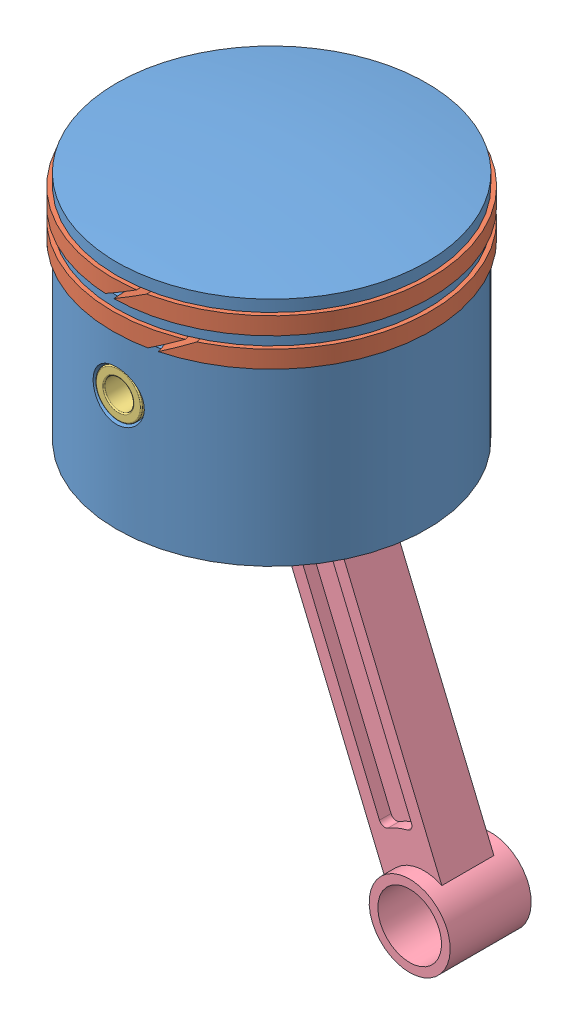
SolidWorks assembly Assem5, configuration Default. Lengths in mm.
Overall size (74.37 104.97 68.73).
5 component instances, 4 part files, 9 mates.
Components (placement in the parent):
- Piston corrected-1: Piston corrected [Default] at (24.7204 8.2179 37.8092) size (53.6 42 53.6)
- Piston Ring-1: Piston Ring [Default] at (24.7204 38.2179 37.8092) x (0.955848 0 -0.293863) z (0.293863 0 0.955848) size (55 3 55)
- Piston Ring-2: Piston Ring [Default] at (24.7204 43.2179 37.8092) x (0.998816 0 -0.048648) z (0.048648 0 0.998816) size (55 3 55)
- Connectoing rod-1: Connectoing rod [Default] at (24.7204 28.2179 37.8092) x (-0.982824 -0.184546 0) z (-0.184546 0.982824 0) size (8 53 8)
- Connecting Rod for piston-1: Connecting Rod for piston [Default] at (55.5687 -45.5953 37.8092) x (0.922665 0.385603 0) z (0 0 1) size (14 94 14)
Mates (geometry in assembly coordinates):
- Concentric1: concentric: cylinder of Piston corrected-1 through (24.7204 74.9973 37.8092) axis (0 1 0) radius 23.8; cylinder of Piston Ring-1 through (24.7204 41.2179 37.8092) axis (0 -1 0) radius 23.8
- Width1: width anti-aligned: plane of Piston Ring-1 through (24.7204 41.2179 37.8092) normal (0 1 0); plane of Piston corrected-1 through (24.7204 38.2179 37.8092) normal (0 -1 0); plane of Piston Ring-1 through (24.7204 41.2179 37.8092) normal (0 -1 0); plane of Piston corrected-1 through (24.7204 38.2179 37.8092) normal (0 1 0)
- Concentric2: concentric: cylinder of Piston corrected-1 through (24.7204 74.9973 37.8092) axis (0 1 0) radius 23.8; cylinder of Piston Ring-2 through (24.7204 46.2179 37.8092) axis (0 -1 0) radius 23.8
- Width2: width anti-aligned: plane of Piston Ring-2 through (24.7204 46.2179 37.8092) normal (0 1 0); plane of Piston corrected-1 through (24.7204 43.2179 37.8092) normal (0 -1 0); plane of Piston Ring-2 through (24.7204 46.2179 37.8092) normal (0 -1 0); plane of Piston corrected-1 through (24.7204 43.2179 37.8092) normal (0 1 0)
- Concentric3: concentric anti-aligned: cylinder of Piston corrected-1 through (24.7204 28.2179 11.0092) axis (0 0 1) radius 4; cylinder of Connectoing rod-1 through (24.7204 28.2179 64.3092) axis (0 0 -1) radius 4
- Concentric4: concentric anti-aligned: cylinder of Piston corrected-1 through (24.7204 28.2179 11.0092) axis (0 0 1) radius 4; cylinder of Connectoing rod-1 through (24.7204 28.2179 64.3092) axis (0 0 -1) radius 4
- Width3: width: plane of Connectoing rod-1 through (24.7204 28.2179 64.3092) normal (0 0 1); plane of Piston corrected-1 through (24.7204 28.2179 11.3092) normal (0 0 -1); cylinder of Connectoing rod-1 through (24.7204 74.9973 37.8092) axis (0 1 0) radius 26.8
- Concentric5: concentric aligned: cylinder of Connectoing rod-1 through (24.7204 28.2179 64.3092) axis (0 0 -1) radius 4; cylinder of Connecting Rod for piston-1 through (24.7204 28.2179 95.7681) axis (0 0 -1) radius 4
- Width4: width: plane of Connecting Rod for piston-1 through (24.7204 28.2179 44.8092) normal (0 0 1); plane of Piston corrected-1 through (24.7204 28.2179 30.8092) normal (0 0 -1); cylinder of Connecting Rod for piston-1 through (24.7204 38.2179 37.8092) axis (0 -1 0) radius 22
